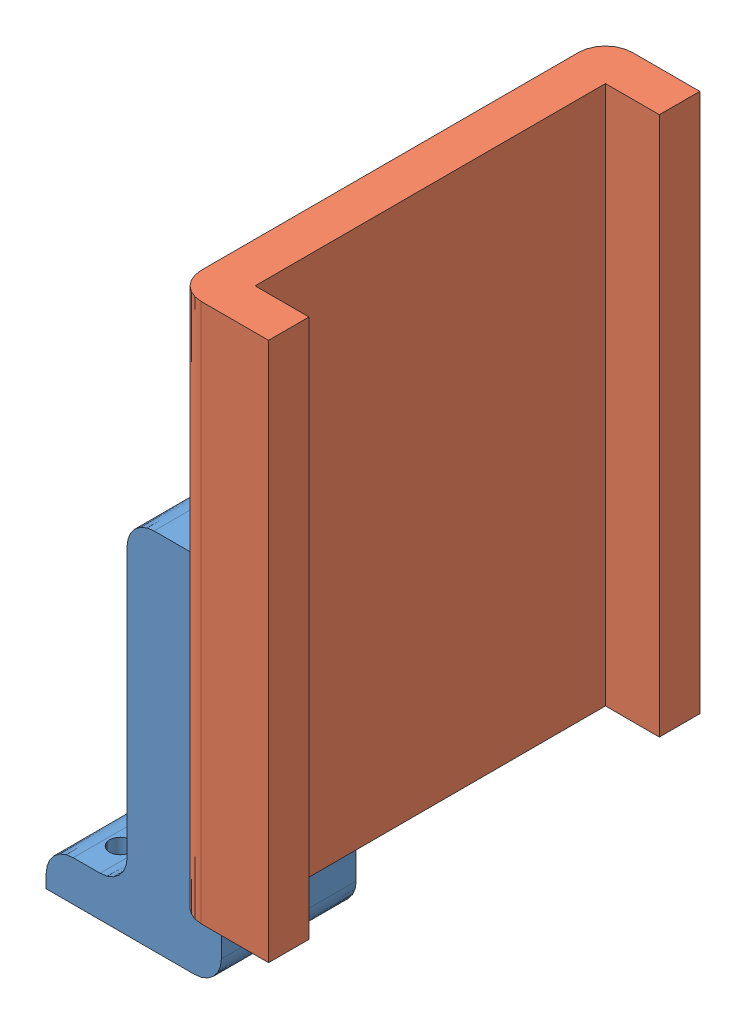
SolidWorks assembly npx_holder_with_leg_5mm, configuration Default. Lengths in mm.
Overall size (6.25 13 8).
2 component instances, 2 part files, 4 mates.
Components (placement in the parent):
- littlel-1: littlel [Default] at (3.5539 4.8106 4.4198) size (4.5 6.75 2.5)
- npx_holder_shaft-1: npx_holder_shaft [Default] at (5.0896 8.0606 4.4198) x (0 0 -1) z (1 0 0) size (8 10 1.75)
Mates (geometry in assembly coordinates):
- Coincident1: coincident: plane of assembly through (0 0 0) normal (0 0 1); plane of littlel-1 through (3.5539 4.8106 4.4198) normal (0 0 1); plane of assembly
- Coincident3: coincident anti-aligned: plane of littlel-1 through (5.0896 4.8106 3.7948) normal (1 0 0); plane of npx_holder_shaft-1 through (5.0896 8.0606 4.4198) normal (-1 0 0)
- Coincident4: coincident anti-aligned: plane of littlel-1 through (3.5539 4.8106 4.4198) normal (0 0 1); plane of npx_holder_shaft-1 through (5.0896 8.0606 4.4198) normal (0 0 -1)
- Distance1: distance = 2 mm: line of littlel-1 through (2.0896 5.0606 4.4198) axis (1 0 0); plane of npx_holder_shaft-1 through (5.8396 3.0606 4.4198) normal (0 -1 0)
